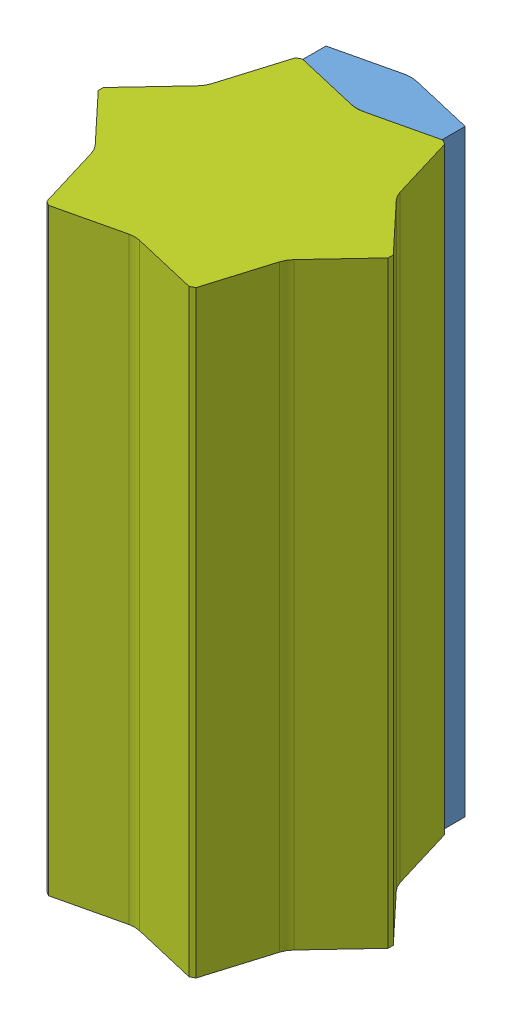
SolidWorks assembly Array-1-III, configuration 默认. Lengths in mm.
Overall size (737 1520 876.05).
163 component instances, 7 part files, 3 mates.
Components (placement in the parent):
- String-III-1: String-III [默认] at (305.6537 41.058 0) size (538.95 1520 404.36)
  - StringBox-III-1: StringBox-III [默认] at (25.091 -857.2069 1520) size (354 1520 138)
  - Unit-III-1: Unit-III [默认] at (25.091 -850.6069 1520) size (538.95 85.58 404.36)
    - OuterShell-III-1: OuterShell-III [默认] at origin size (538.95 73.59 404.36)
    - InnerUnit-1: InnerUnit [默认] at (-1.9481 30.6195 80) x (1 0 0) z (0 0 -1) size (102 85 103.7)
      - BEGeDet-2: BEGeDet [默认] at (1.9481 14.6195 80) x (1 0 0) z (0 0 -1) size (80 40 80)
      - InnerShell-3: InnerShell [默认] at (1.9481 -36.3805 80) size (102 61 102)
      - Electronics-1: Electronics [默认] at (1.9481 24.7195 80) x (-1 0 0) z (0 0 1) size (21.21 85 103.7)
    - SiPMArray-1: SiPMArray [默认] at (165 35.3248 0) size (10.4 81 40.4)
    - SiPMArray-2: SiPMArray [默认] at (-165 35.3248 0) x (-1 0 0) z (0 0 -1) size (10.4 81 40.4)
  - Unit-III-2: Unit-III [默认] at (25.091 -778.6069 1520) size (538.95 85.58 404.36)
    - OuterShell-III-1: OuterShell-III [默认] at origin size (538.95 73.59 404.36)
    - InnerUnit-1: InnerUnit [默认] at (-1.9481 30.6195 80) x (1 0 0) z (0 0 -1) size (102 85 103.7)
      - BEGeDet-2: BEGeDet [默认] at (1.9481 14.6195 80) x (1 0 0) z (0 0 -1) size (80 40 80)
      - InnerShell-3: InnerShell [默认] at (1.9481 -36.3805 80) size (102 61 102)
      - Electronics-1: Electronics [默认] at (1.9481 24.7195 80) x (-1 0 0) z (0 0 1) size (21.21 85 103.7)
    - SiPMArray-1: SiPMArray [默认] at (165 35.3248 0) size (10.4 81 40.4)
    - SiPMArray-2: SiPMArray [默认] at (-165 35.3248 0) x (-1 0 0) z (0 0 -1) size (10.4 81 40.4)
  - Unit-III-3: Unit-III [默认] at (25.091 -706.6069 1520) size (538.95 85.58 404.36)
    - OuterShell-III-1: OuterShell-III [默认] at origin size (538.95 73.59 404.36)
    - InnerUnit-1: InnerUnit [默认] at (-1.9481 30.6195 80) x (1 0 0) z (0 0 -1) size (102 85 103.7)
      - BEGeDet-2: BEGeDet [默认] at (1.9481 14.6195 80) x (1 0 0) z (0 0 -1) size (80 40 80)
      - InnerShell-3: InnerShell [默认] at (1.9481 -36.3805 80) size (102 61 102)
      - Electronics-1: Electronics [默认] at (1.9481 24.7195 80) x (-1 0 0) z (0 0 1) size (21.21 85 103.7)
    - SiPMArray-1: SiPMArray [默认] at (165 35.3248 0) size (10.4 81 40.4)
    - SiPMArray-2: SiPMArray [默认] at (-165 35.3248 0) x (-1 0 0) z (0 0 -1) size (10.4 81 40.4)
  - Unit-III-4: Unit-III [默认] at (25.091 -634.6069 1520) size (538.95 85.58 404.36)
    - OuterShell-III-1: OuterShell-III [默认] at origin size (538.95 73.59 404.36)
    - InnerUnit-1: InnerUnit [默认] at (-1.9481 30.6195 80) x (1 0 0) z (0 0 -1) size (102 85 103.7)
      - BEGeDet-2: BEGeDet [默认] at (1.9481 14.6195 80) x (1 0 0) z (0 0 -1) size (80 40 80)
      - InnerShell-3: InnerShell [默认] at (1.9481 -36.3805 80) size (102 61 102)
      - Electronics-1: Electronics [默认] at (1.9481 24.7195 80) x (-1 0 0) z (0 0 1) size (21.21 85 103.7)
    - SiPMArray-1: SiPMArray [默认] at (165 35.3248 0) size (10.4 81 40.4)
    - SiPMArray-2: SiPMArray [默认] at (-165 35.3248 0) x (-1 0 0) z (0 0 -1) size (10.4 81 40.4)
  - Unit-III-5: Unit-III [默认] at (25.091 -562.6069 1520) size (538.95 85.58 404.36)
    - OuterShell-III-1: OuterShell-III [默认] at origin size (538.95 73.59 404.36)
    - InnerUnit-1: InnerUnit [默认] at (-1.9481 30.6195 80) x (1 0 0) z (0 0 -1) size (102 85 103.7)
      - BEGeDet-2: BEGeDet [默认] at (1.9481 14.6195 80) x (1 0 0) z (0 0 -1) size (80 40 80)
      - InnerShell-3: InnerShell [默认] at (1.9481 -36.3805 80) size (102 61 102)
      - Electronics-1: Electronics [默认] at (1.9481 24.7195 80) x (-1 0 0) z (0 0 1) size (21.21 85 103.7)
    - SiPMArray-1: SiPMArray [默认] at (165 35.3248 0) size (10.4 81 40.4)
    - SiPMArray-2: SiPMArray [默认] at (-165 35.3248 0) x (-1 0 0) z (0 0 -1) size (10.4 81 40.4)
  - Unit-III-6: Unit-III [默认] at (25.091 -490.6069 1520) size (538.95 85.58 404.36)
    - OuterShell-III-1: OuterShell-III [默认] at origin size (538.95 73.59 404.36)
    - InnerUnit-1: InnerUnit [默认] at (-1.9481 30.6195 80) x (1 0 0) z (0 0 -1) size (102 85 103.7)
      - BEGeDet-2: BEGeDet [默认] at (1.9481 14.6195 80) x (1 0 0) z (0 0 -1) size (80 40 80)
      - InnerShell-3: InnerShell [默认] at (1.9481 -36.3805 80) size (102 61 102)
      - Electronics-1: Electronics [默认] at (1.9481 24.7195 80) x (-1 0 0) z (0 0 1) size (21.21 85 103.7)
    - SiPMArray-1: SiPMArray [默认] at (165 35.3248 0) size (10.4 81 40.4)
    - SiPMArray-2: SiPMArray [默认] at (-165 35.3248 0) x (-1 0 0) z (0 0 -1) size (10.4 81 40.4)
  - Unit-III-7: Unit-III [默认] at (25.091 -418.6069 1520) size (538.95 85.58 404.36)
    - OuterShell-III-1: OuterShell-III [默认] at origin size (538.95 73.59 404.36)
    - InnerUnit-1: InnerUnit [默认] at (-1.9481 30.6195 80) x (1 0 0) z (0 0 -1) size (102 85 103.7)
      - BEGeDet-2: BEGeDet [默认] at (1.9481 14.6195 80) x (1 0 0) z (0 0 -1) size (80 40 80)
      - InnerShell-3: InnerShell [默认] at (1.9481 -36.3805 80) size (102 61 102)
      - Electronics-1: Electronics [默认] at (1.9481 24.7195 80) x (-1 0 0) z (0 0 1) size (21.21 85 103.7)
    - SiPMArray-1: SiPMArray [默认] at (165 35.3248 0) size (10.4 81 40.4)
    - SiPMArray-2: SiPMArray [默认] at (-165 35.3248 0) x (-1 0 0) z (0 0 -1) size (10.4 81 40.4)
  - Unit-III-8: Unit-III [默认] at (25.091 -346.6069 1520) size (538.95 85.58 404.36)
    - OuterShell-III-1: OuterShell-III [默认] at origin size (538.95 73.59 404.36)
    - InnerUnit-1: InnerUnit [默认] at (-1.9481 30.6195 80) x (1 0 0) z (0 0 -1) size (102 85 103.7)
      - BEGeDet-2: BEGeDet [默认] at (1.9481 14.6195 80) x (1 0 0) z (0 0 -1) size (80 40 80)
      - InnerShell-3: InnerShell [默认] at (1.9481 -36.3805 80) size (102 61 102)
      - Electronics-1: Electronics [默认] at (1.9481 24.7195 80) x (-1 0 0) z (0 0 1) size (21.21 85 103.7)
    - SiPMArray-1: SiPMArray [默认] at (165 35.3248 0) size (10.4 81 40.4)
    - SiPMArray-2: SiPMArray [默认] at (-165 35.3248 0) x (-1 0 0) z (0 0 -1) size (10.4 81 40.4)
  - Unit-III-9: Unit-III [默认] at (25.091 -274.6069 1520) size (538.95 85.58 404.36)
    - OuterShell-III-1: OuterShell-III [默认] at origin size (538.95 73.59 404.36)
    - InnerUnit-1: InnerUnit [默认] at (-1.9481 30.6195 80) x (1 0 0) z (0 0 -1) size (102 85 103.7)
      - BEGeDet-2: BEGeDet [默认] at (1.9481 14.6195 80) x (1 0 0) z (0 0 -1) size (80 40 80)
      - InnerShell-3: InnerShell [默认] at (1.9481 -36.3805 80) size (102 61 102)
      - Electronics-1: Electronics [默认] at (1.9481 24.7195 80) x (-1 0 0) z (0 0 1) size (21.21 85 103.7)
    - SiPMArray-1: SiPMArray [默认] at (165 35.3248 0) size (10.4 81 40.4)
    - SiPMArray-2: SiPMArray [默认] at (-165 35.3248 0) x (-1 0 0) z (0 0 -1) size (10.4 81 40.4)
  - Unit-III-10: Unit-III [默认] at (25.091 -202.6069 1520) size (538.95 85.58 404.36)
    - OuterShell-III-1: OuterShell-III [默认] at origin size (538.95 73.59 404.36)
    - InnerUnit-1: InnerUnit [默认] at (-1.9481 30.6195 80) x (1 0 0) z (0 0 -1) size (102 85 103.7)
      - BEGeDet-2: BEGeDet [默认] at (1.9481 14.6195 80) x (1 0 0) z (0 0 -1) size (80 40 80)
      - InnerShell-3: InnerShell [默认] at (1.9481 -36.3805 80) size (102 61 102)
      - Electronics-1: Electronics [默认] at (1.9481 24.7195 80) x (-1 0 0) z (0 0 1) size (21.21 85 103.7)
    - SiPMArray-1: SiPMArray [默认] at (165 35.3248 0) size (10.4 81 40.4)
    - SiPMArray-2: SiPMArray [默认] at (-165 35.3248 0) x (-1 0 0) z (0 0 -1) size (10.4 81 40.4)
  - Unit-III-11: Unit-III [默认] at (25.091 -130.6069 1520) size (538.95 85.58 404.36)
    - OuterShell-III-1: OuterShell-III [默认] at origin size (538.95 73.59 404.36)
    - InnerUnit-1: InnerUnit [默认] at (-1.9481 30.6195 80) x (1 0 0) z (0 0 -1) size (102 85 103.7)
      - BEGeDet-2: BEGeDet [默认] at (1.9481 14.6195 80) x (1 0 0) z (0 0 -1) size (80 40 80)
      - InnerShell-3: InnerShell [默认] at (1.9481 -36.3805 80) size (102 61 102)
      - Electronics-1: Electronics [默认] at (1.9481 24.7195 80) x (-1 0 0) z (0 0 1) size (21.21 85 103.7)
    - SiPMArray-1: SiPMArray [默认] at (165 35.3248 0) size (10.4 81 40.4)
    - SiPMArray-2: SiPMArray [默认] at (-165 35.3248 0) x (-1 0 0) z (0 0 -1) size (10.4 81 40.4)
  - Unit-III-12: Unit-III [默认] at (25.091 -58.6069 1520) size (538.95 85.58 404.36)
    - OuterShell-III-1: OuterShell-III [默认] at origin size (538.95 73.59 404.36)
    - InnerUnit-1: InnerUnit [默认] at (-1.9481 30.6195 80) x (1 0 0) z (0 0 -1) size (102 85 103.7)
      - BEGeDet-2: BEGeDet [默认] at (1.9481 14.6195 80) x (1 0 0) z (0 0 -1) size (80 40 80)
      - InnerShell-3: InnerShell [默认] at (1.9481 -36.3805 80) size (102 61 102)
      - Electronics-1: Electronics [默认] at (1.9481 24.7195 80) x (-1 0 0) z (0 0 1) size (21.21 85 103.7)
    - SiPMArray-1: SiPMArray [默认] at (165 35.3248 0) size (10.4 81 40.4)
    - SiPMArray-2: SiPMArray [默认] at (-165 35.3248 0) x (-1 0 0) z (0 0 -1) size (10.4 81 40.4)
  - Unit-III-13: Unit-III [默认] at (25.091 13.3931 1520) size (538.95 85.58 404.36)
    - OuterShell-III-1: OuterShell-III [默认] at origin size (538.95 73.59 404.36)
    - InnerUnit-1: InnerUnit [默认] at (-1.9481 30.6195 80) x (1 0 0) z (0 0 -1) size (102 85 103.7)
      - BEGeDet-2: BEGeDet [默认] at (1.9481 14.6195 80) x (1 0 0) z (0 0 -1) size (80 40 80)
      - InnerShell-3: InnerShell [默认] at (1.9481 -36.3805 80) size (102 61 102)
      - Electronics-1: Electronics [默认] at (1.9481 24.7195 80) x (-1 0 0) z (0 0 1) size (21.21 85 103.7)
    - SiPMArray-1: SiPMArray [默认] at (165 35.3248 0) size (10.4 81 40.4)
    - SiPMArray-2: SiPMArray [默认] at (-165 35.3248 0) x (-1 0 0) z (0 0 -1) size (10.4 81 40.4)
  - Unit-III-14: Unit-III [默认] at (25.091 85.3931 1520) size (538.95 85.58 404.36)
    - OuterShell-III-1: OuterShell-III [默认] at origin size (538.95 73.59 404.36)
    - InnerUnit-1: InnerUnit [默认] at (-1.9481 30.6195 80) x (1 0 0) z (0 0 -1) size (102 85 103.7)
      - BEGeDet-2: BEGeDet [默认] at (1.9481 14.6195 80) x (1 0 0) z (0 0 -1) size (80 40 80)
      - InnerShell-3: InnerShell [默认] at (1.9481 -36.3805 80) size (102 61 102)
      - Electronics-1: Electronics [默认] at (1.9481 24.7195 80) x (-1 0 0) z (0 0 1) size (21.21 85 103.7)
    - SiPMArray-1: SiPMArray [默认] at (165 35.3248 0) size (10.4 81 40.4)
    - SiPMArray-2: SiPMArray [默认] at (-165 35.3248 0) x (-1 0 0) z (0 0 -1) size (10.4 81 40.4)
  - Unit-III-15: Unit-III [默认] at (25.091 157.3931 1520) size (538.95 85.58 404.36)
    - OuterShell-III-1: OuterShell-III [默认] at origin size (538.95 73.59 404.36)
    - InnerUnit-1: InnerUnit [默认] at (-1.9481 30.6195 80) x (1 0 0) z (0 0 -1) size (102 85 103.7)
      - BEGeDet-2: BEGeDet [默认] at (1.9481 14.6195 80) x (1 0 0) z (0 0 -1) size (80 40 80)
      - InnerShell-3: InnerShell [默认] at (1.9481 -36.3805 80) size (102 61 102)
      - Electronics-1: Electronics [默认] at (1.9481 24.7195 80) x (-1 0 0) z (0 0 1) size (21.21 85 103.7)
    - SiPMArray-1: SiPMArray [默认] at (165 35.3248 0) size (10.4 81 40.4)
    - SiPMArray-2: SiPMArray [默认] at (-165 35.3248 0) x (-1 0 0) z (0 0 -1) size (10.4 81 40.4)
  - Unit-III-16: Unit-III [默认] at (25.091 229.3931 1520) size (538.95 85.58 404.36)
    - OuterShell-III-1: OuterShell-III [默认] at origin size (538.95 73.59 404.36)
    - InnerUnit-1: InnerUnit [默认] at (-1.9481 30.6195 80) x (1 0 0) z (0 0 -1) size (102 85 103.7)
      - BEGeDet-2: BEGeDet [默认] at (1.9481 14.6195 80) x (1 0 0) z (0 0 -1) size (80 40 80)
      - InnerShell-3: InnerShell [默认] at (1.9481 -36.3805 80) size (102 61 102)
      - Electronics-1: Electronics [默认] at (1.9481 24.7195 80) x (-1 0 0) z (0 0 1) size (21.21 85 103.7)
    - SiPMArray-1: SiPMArray [默认] at (165 35.3248 0) size (10.4 81 40.4)
    - SiPMArray-2: SiPMArray [默认] at (-165 35.3248 0) x (-1 0 0) z (0 0 -1) size (10.4 81 40.4)
  - Unit-III-17: Unit-III [默认] at (25.091 301.3931 1520) size (538.95 85.58 404.36)
    - OuterShell-III-1: OuterShell-III [默认] at origin size (538.95 73.59 404.36)
    - InnerUnit-1: InnerUnit [默认] at (-1.9481 30.6195 80) x (1 0 0) z (0 0 -1) size (102 85 103.7)
      - BEGeDet-2: BEGeDet [默认] at (1.9481 14.6195 80) x (1 0 0) z (0 0 -1) size (80 40 80)
      - InnerShell-3: InnerShell [默认] at (1.9481 -36.3805 80) size (102 61 102)
      - Electronics-1: Electronics [默认] at (1.9481 24.7195 80) x (-1 0 0) z (0 0 1) size (21.21 85 103.7)
    - SiPMArray-1: SiPMArray [默认] at (165 35.3248 0) size (10.4 81 40.4)
    - SiPMArray-2: SiPMArray [默认] at (-165 35.3248 0) x (-1 0 0) z (0 0 -1) size (10.4 81 40.4)
  - Unit-III-18: Unit-III [默认] at (25.091 373.3931 1520) size (538.95 85.58 404.36)
    - OuterShell-III-1: OuterShell-III [默认] at origin size (538.95 73.59 404.36)
    - InnerUnit-1: InnerUnit [默认] at (-1.9481 30.6195 80) x (1 0 0) z (0 0 -1) size (102 85 103.7)
      - BEGeDet-2: BEGeDet [默认] at (1.9481 14.6195 80) x (1 0 0) z (0 0 -1) size (80 40 80)
      - InnerShell-3: InnerShell [默认] at (1.9481 -36.3805 80) size (102 61 102)
      - Electronics-1: Electronics [默认] at (1.9481 24.7195 80) x (-1 0 0) z (0 0 1) size (21.21 85 103.7)
    - SiPMArray-1: SiPMArray [默认] at (165 35.3248 0) size (10.4 81 40.4)
    - SiPMArray-2: SiPMArray [默认] at (-165 35.3248 0) x (-1 0 0) z (0 0 -1) size (10.4 81 40.4)
  - Unit-III-19: Unit-III [默认] at (25.091 445.3931 1520) size (538.95 85.58 404.36)
    - OuterShell-III-1: OuterShell-III [默认] at origin size (538.95 73.59 404.36)
    - InnerUnit-1: InnerUnit [默认] at (-1.9481 30.6195 80) x (1 0 0) z (0 0 -1) size (102 85 103.7)
      - BEGeDet-2: BEGeDet [默认] at (1.9481 14.6195 80) x (1 0 0) z (0 0 -1) size (80 40 80)
      - InnerShell-3: InnerShell [默认] at (1.9481 -36.3805 80) size (102 61 102)
      - Electronics-1: Electronics [默认] at (1.9481 24.7195 80) x (-1 0 0) z (0 0 1) size (21.21 85 103.7)
    - SiPMArray-1: SiPMArray [默认] at (165 35.3248 0) size (10.4 81 40.4)
    - SiPMArray-2: SiPMArray [默认] at (-165 35.3248 0) x (-1 0 0) z (0 0 -1) size (10.4 81 40.4)
  - Unit-III-20: Unit-III [默认] at (25.091 517.3931 1520) size (538.95 85.58 404.36)
    - OuterShell-III-1: OuterShell-III [默认] at origin size (538.95 73.59 404.36)
    - InnerUnit-1: InnerUnit [默认] at (-1.9481 30.6195 80) x (1 0 0) z (0 0 -1) size (102 85 103.7)
      - BEGeDet-2: BEGeDet [默认] at (1.9481 14.6195 80) x (1 0 0) z (0 0 -1) size (80 40 80)
      - InnerShell-3: InnerShell [默认] at (1.9481 -36.3805 80) size (102 61 102)
      - Electronics-1: Electronics [默认] at (1.9481 24.7195 80) x (-1 0 0) z (0 0 1) size (21.21 85 103.7)
    - SiPMArray-1: SiPMArray [默认] at (165 35.3248 0) size (10.4 81 40.4)
    - SiPMArray-2: SiPMArray [默认] at (-165 35.3248 0) x (-1 0 0) z (0 0 -1) size (10.4 81 40.4)
- SArContainer-III-1: SArContainer-III [默认] at (330.7447 -816.1489 1871.4585) size (737 1520 644.82)
Mates (geometry in assembly coordinates):
- 重合15: coincident aligned: plane of String-III-1/StringBox-III-1 through (330.7447 -826.1489 1520) normal (0 -1 0); plane of SArContainer-III-1 through (330.7447 -826.1489 1871.4585) normal (0 -1 0)
- 重合19: coincident anti-aligned: plane of String-III-1/StringBox-III-1 through (161.4647 683.8511 1551.2266) normal (-0.228 0 0.973661); plane of SArContainer-III-1 through (156.0247 1183.8511 1549.9528) normal (0.228 0 -0.973661)
- 重合20: coincident anti-aligned: plane of String-III-1/StringBox-III-1 through (346.4767 683.8511 1587.1826) normal (0.228 0 0.973661); plane of SArContainer-III-1 through (344.1967 1183.8511 1587.7165) normal (-0.228 0 -0.973661)
